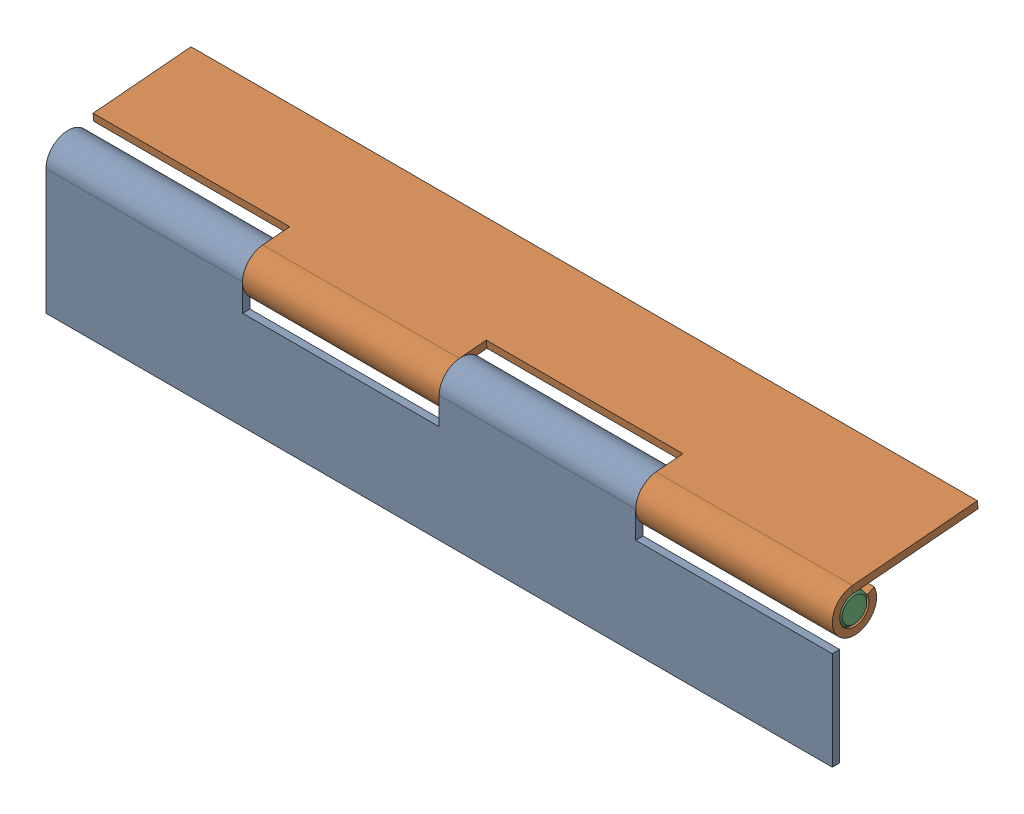
SolidWorks assembly MirrorBASE-Cabinet Hinge, configuration Default. Lengths in mm.
Overall size (160 32.21 30.67).
3 component instances, 2 part files, 4 mates.
Components (placement in the parent):
- MirrorBASE-Cabinet Hinge Flange-1: MirrorBASE-Cabinet Hinge Flange [Default] at (-155.1002 71.3389 -114.9534) size (160 30 9)
- MirrorBASE-Cabinet Hinge Flange-2: MirrorBASE-Cabinet Hinge Flange [Default] at (4.8998 102.05 -143.0949) x (-1 0 0) z (0 0.996195 0.087156) size (160 30 9)
- MirrorBASE-Cabinet Hinge Pin-1: MirrorBASE-Cabinet Hinge Pin [Default] at (-155.1002 93.2182 -117.9534) x (0 0 1) z (-1 0 0) size (6 6 160)
Mates (geometry in assembly coordinates):
- Concentric1: concentric: cylinder of assembly; cylinder of assembly; cylinder of MirrorBASE-Cabinet Hinge Flange-2 through (4.8998 96.8389 -117.9534) axis (1 0 0) radius 3; cylinder of MirrorBASE-Cabinet Hinge Pin-1 through (4.8998 96.8389 -117.9534) axis (-1 0 0) radius 3
- Coincident1: coincident: plane of assembly; plane of assembly; plane of MirrorBASE-Cabinet Hinge Flange-2 through (4.8998 96.8389 -117.9534) normal (1 0 0); plane of MirrorBASE-Cabinet Hinge Pin-1 through (4.8998 96.8389 -117.9534) normal (1 0 0)
- Concentric2: concentric: cylinder of assembly; cylinder of assembly; cylinder of MirrorBASE-Cabinet Hinge Flange-1 through (-75.1002 96.8389 -117.9534) axis (-1 0 0) radius 3; cylinder of MirrorBASE-Cabinet Hinge Pin-1 through (4.8998 96.8389 -117.9534) axis (-1 0 0) radius 3
- Coincident2: coincident: plane of assembly; plane of assembly; plane of MirrorBASE-Cabinet Hinge Flange-1 through (-35.1002 96.8389 -117.9534) normal (1 0 0); plane of MirrorBASE-Cabinet Hinge Flange-2 through (-35.1002 96.8389 -117.9534) normal (-1 0 0)
